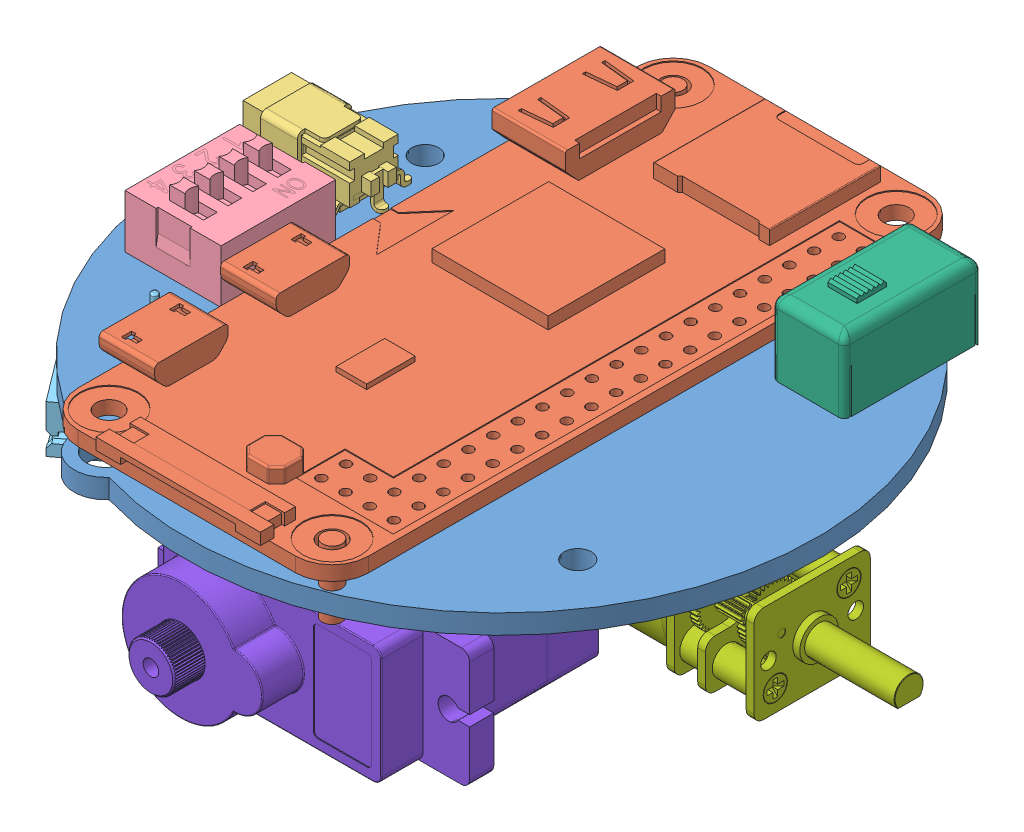
SolidWorks assembly PCB_Placement, configuration Default. Lengths in mm.
Overall size (75 24.45 71.69).
10 component instances, 9 part files, 20 mates.
Components (placement in the parent):
- PCB_Placement-1: PCB_Placement [Default] at (15.5645 37.6421 51.2762) size (65 2 65)
- Pi_Zero_W-1: Pi_Zero_W [Default] at (15.6528 42.1421 51.2764) x (-0.00218 0 0.999998) z (-0.999998 0 -0.00218) size (65.9 10.3 31.25)
- Barrel_jack-1: Barrel_jack [Default] at (-15.4717 39.7421 44.422) x (0 0 1) z (-1 0 0) size (8.2 6 12.3)
- DS-4-1: DS-4 [Default] at (-13.1214 39.6421 49.6228) x (0 0 1) z (-1 0 0) size (11.82 10.4 9.9)
- Yoke_Upper_PCB-1: Yoke_Upper_PCB [Default] at (15.5645 29.4421 51.2762) size (64.98 8.26 64.5) (hidden)
- 022057045-1: 022057045 [Default] at (-7.2138 35.1921 70.15) x (0.601753 0 0.798683) z (0 -1 0) size (12.4 7.9 8.4)
- 25136nab-1: 25136nab [Default] at (35.2883 39.6421 32.33) x (0.00218 0 -0.999998) z (0 1 0) size (14.12 7.51 12.24)
- N20_motor_magnetic_encoder-1: N20_motor_magnetic_encoder [Default] at (23.9035 33.7918 61.3271) x (0 0 1) z (1 0 0) size (12.01 10.84 40.2)
- Servo_motor-1: Servo_motor [Peça] at (20.3543 29.5421 67.8236) x (0.999999 0 -0.001445) z (0 -1 0) size (32.1 29.95 12.4)
- Servo_motor-2: Servo_motor [Peça] at (11.2543 29.5421 34.7533) x (-1 0 0) z (0 -1 0) size (32.1 29.95 12.4)
Mates (geometry in assembly coordinates):
- Distance2: distance = 2.5 mm anti-aligned: plane of Pi_Zero_W-1 through (26.9654 42.1421 22.5509) normal (0 -1 0); plane of PCB_Placement-1 through (21.4895 39.6421 36.7762) normal (0 1 0)
- Tangent3: tangent aligned: cylinder of PCB_Placement-1 through (15.5645 39.6421 51.2762) axis (0 -1 0) radius 32.5; plane of Pi_Zero_W-1 through (26.9736 43.6421 18.801) normal (0.00218 0 -0.999998)
- Coincident6: coincident anti-aligned: plane of PCB_Placement-1 through (21.4895 39.6421 36.7762) normal (0 1 0); plane of Barrel_jack-1 through (-13.9494 39.6421 48.522) normal (0 -1 0)
- Coincident7: coincident anti-aligned: plane of PCB_Placement-1 through (21.4895 39.6421 36.7762) normal (0 1 0); plane of DS-4-1 through (-13.1214 39.6421 49.6228) normal (0 -1 0)
- Concentric1: concentric aligned: cylinder of PCB_Placement-1 through (15.5645 39.6421 51.2762) axis (0 -1 0) radius 32.5; cylinder of Yoke_Upper_PCB-1 through (15.5645 35.1421 51.2762) axis (0 -1 0) radius 32.5
- Coincident8: coincident aligned: plane of PCB_Placement-1 through (15.5645 37.6421 51.2762) normal (0 0 1); plane of Yoke_Upper_PCB-1 through (15.5645 29.4421 51.2762) normal (0 0 1)
- Concentric2: concentric anti-aligned: cylinder of Pi_Zero_W-1 through (4.0645 42.1421 80.2762) axis (0 1 0) radius 1.325; cylinder of Yoke_Upper_PCB-1 through (4.0645 31.9421 80.2762) axis (0 -1 0) radius 2
- Parallel3: parallel anti-aligned: cylinder of Pi_Zero_W-1 through (27.241 42.1421 22.2765) axis (0 1 0) radius 1.325; cylinder of Yoke_Upper_PCB-1 through (27.0645 31.9421 22.2762) axis (0 -1 0) radius 2
- Coincident12: coincident anti-aligned: plane of PCB_Placement-1 through (21.4895 37.6421 36.7762) normal (0 -1 0); plane of 022057045-1 through (-1.1268 37.6421 73.3266) normal (0 1 0)
- Tangent7: tangent aligned: cylinder of PCB_Placement-1 through (15.5645 39.6421 51.2762) axis (0 -1 0) radius 32.5; plane of 022057045-1 through (-9.5699 35.1921 71.9251) normal (-0.798683 0 0.601753)
- Coincident13: coincident anti-aligned: plane of PCB_Placement-1 through (21.4895 39.6421 36.7762) normal (0 1 0); plane of 25136nab-1 through (35.2883 39.6421 32.33) normal (0 -1 0)
- Coincident15: coincident anti-aligned: plane of Yoke_Upper_PCB-1 through (48.0454 36.1421 51.2998) normal (0 -1 0); plane of N20_motor_magnetic_encoder-1 through (25.0645 36.1421 51.7762) normal (0 1 0)
- Tangent8: tangent aligned: cylinder of Yoke_Upper_PCB-1 through (15.5645 31.9421 51.2762) axis (0 -1 0) radius 32.5; plane of N20_motor_magnetic_encoder-1 through (48.0645 26.1421 45.7762) normal (1 0 0)
- Tangent9: tangent anti-aligned: plane of Yoke_Upper_PCB-1 through (15.5645 36.1421 45.7762) normal (0 0 1); cylinder of N20_motor_magnetic_encoder-1 through (25.0645 31.1421 51.7762) axis (1 0 0) radius 6
- Coincident17: coincident anti-aligned: plane of Yoke_Upper_PCB-1 through (32.7945 35.6421 72.4562) normal (0 -1 0); plane of Servo_motor-1 through (5.1654 35.6421 75.4955) normal (0 1 0)
- Distance3: distance = 0.5 mm anti-aligned: plane of Yoke_Upper_PCB-1 through (15.5952 31.9421 72.4804) normal (0.001445 0 0.999999); plane of Servo_motor-1 through (5.1618 24.2921 72.9955) normal (-0.001445 0 -0.999999)
- Coincident20: coincident anti-aligned: plane of Yoke_Upper_PCB-1 through (-1.6692 35.6421 30.1033) normal (0 -1 0); plane of Servo_motor-2 through (26.4543 35.6421 27.1033) normal (0 1 0)
- Distance4: distance = 0.5 mm anti-aligned: plane of Yoke_Upper_PCB-1 through (15.5645 31.9421 30.1033) normal (0 0 -1); plane of Servo_motor-2 through (26.4543 24.2921 29.6033) normal (0 0 1)
- Coincident22: coincident anti-aligned: plane of PCB_Placement-1 through (21.4895 37.6421 36.7762) normal (0 -1 0); plane of Yoke_Upper_PCB-1 through (-16.9354 37.6421 51.2468) normal (0 1 0)
- Parallel4: parallel anti-aligned: plane of Pi_Zero_W-1 through (30.7154 43.6421 22.5591) normal (0.999998 0 0.00218); plane of 25136nab-1 through (31.5521 39.6421 25.9719) normal (-0.999998 0 -0.00218)
